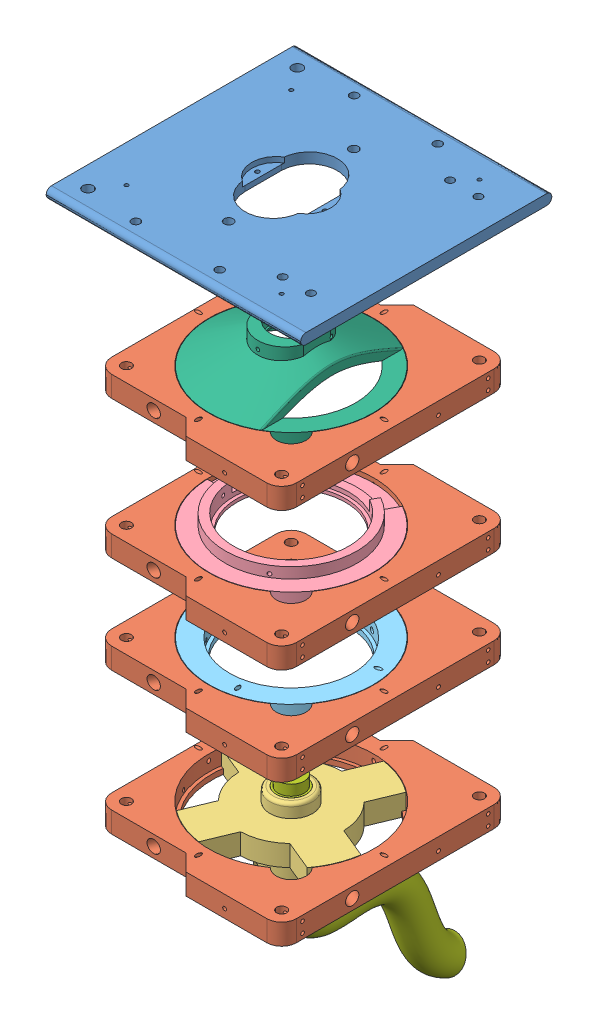
SolidWorks assembly opticalcage, configuration Default. Lengths in mm.
Overall size (154.43 460.49 175.46).
10 component instances, 7 part files, 20 mates.
Components (placement in the parent):
- peltier_TopPlate_off100-1: peltier_TopPlate_off100 [Default] at (-91.0446 13.6016 38.8023) size (154.43 6.35 152.4)
- 100mm_lensholder_and_base_off100-1: 100mm_lensholder_and_base_off100 [Default] at (-18.5446 -316.5942 -37.3977) x (-1 0 0) z (0 0 -1) size (122.18 12.7 138)
- lightpipeholder-1: lightpipeholder [Default] at (-18.5446 -339.6442 -37.3977) x (0.92388 0 0.382683) z (-0.382683 0 0.92388) size (99.4 44 99.4)
- 100mm_lensholder_and_base_off100-2: 100mm_lensholder_and_base_off100 [Default] at (-18.5446 -230.4526 -37.3977) x (-1 0 0) z (0 0 -1) size (122.18 12.7 138)
- 100mm_lensholder_and_base_off100-3: 100mm_lensholder_and_base_off100 [Default] at (-18.5446 -171.4721 -37.3977) x (-1 0 0) z (0 0 -1) size (122.18 12.7 138)
- 100mm_lensholder_and_base_off100-4: 100mm_lensholder_and_base_off100 [Default] at (-18.5446 -87.6141 -37.3977) x (-1 0 0) z (0 0 -1) size (122.18 12.7 138)
- 70mm_irisholder-1: 70mm_irisholder [Default] at (-18.5446 -171.4721 -37.3977) x (-0.382683 0 0.92388) z (-0.92388 0 -0.382683) size (99.4 19.2 99.4)
- 75mm_lensholder-1: 75mm_lensholder [Default] at (-18.5446 -230.4526 -37.3977) x (0.92388 0 0.382683) z (-0.382683 0 0.92388) size (99.4 12.7 99.4)
- 1in_lensholder-1: 1in_lensholder [Default] at (-18.5446 -87.6141 -37.3977) x (0 0 1) z (-1 0 0) size (99.4 36.04 99.4)
- lightpipe-1: lightpipe [Default] at (-18.5446 -289.2942 -37.3977) size (25 151.24 111.76)
Mates (geometry in assembly coordinates):
- Concentric4: concentric aligned: cylinder of peltier_TopPlate_off100-1 through (35.6379 19.9516 22.6023) axis (0 -1 0) radius 1.128; cylinder of 100mm_lensholder_and_base_off100-1 through (35.6379 -303.8942 22.6023) axis (0 -1 0) radius 3.025
- Concentric5: concentric aligned: cylinder of peltier_TopPlate_off100-1 through (-68.5446 19.9516 -87.3977) axis (0 -1 0) radius 1.128; cylinder of 100mm_lensholder_and_base_off100-1 through (-68.5446 -303.8942 -87.3977) axis (0 -1 0) radius 3.025
- Concentric6: concentric aligned: cylinder of 100mm_lensholder_and_base_off100-1 through (-51.5802 -310.2442 42.3571) axis (0.382683 0 -0.92388) radius 2.1; cylinder of lightpipeholder-1 through (-37.564 -310.2442 8.5191) axis (0.382683 0 -0.92388) radius 1.6425
- Concentric7: concentric aligned: cylinder of 100mm_lensholder_and_base_off100-1 through (59.7802 -310.2442 -4.9545) axis (-0.92388 0 -0.382683) radius 3.75; cylinder of lightpipeholder-1 through (27.3722 -310.2442 -18.3783) axis (-0.92388 0 -0.382683) radius 1.6425
- Concentric11: concentric aligned: circle of 100mm_lensholder_and_base_off100-2; circle of 100mm_lensholder_and_base_off100-3
- Concentric12: concentric aligned: circle of 100mm_lensholder_and_base_off100-1; circle of 100mm_lensholder_and_base_off100-2
- Concentric13: concentric aligned: circle of 100mm_lensholder_and_base_off100-3; circle of 100mm_lensholder_and_base_off100-4
- Concentric14: concentric aligned: circle of 100mm_lensholder_and_base_off100-3; circle of 100mm_lensholder_and_base_off100-4
- Concentric15: concentric aligned: circle of 100mm_lensholder_and_base_off100-2; circle of 100mm_lensholder_and_base_off100-3
- Concentric16: concentric aligned: circle of 100mm_lensholder_and_base_off100-1; circle of 100mm_lensholder_and_base_off100-2
- Concentric17: concentric aligned: cylinder of 100mm_lensholder_and_base_off100-2 through (-18.5446 -230.4526 -37.3977) axis (0 -1 0) radius 50; cylinder of 75mm_lensholder-1 through (-18.5446 -230.4526 -37.3977) axis (0 -1 0) radius 37.5
- Concentric18: concentric aligned: cylinder of 100mm_lensholder_and_base_off100-2 through (15.1034 -224.1026 -118.6313) axis (-0.382683 0 0.92388) radius 3.75; cylinder of 75mm_lensholder-1 through (0.4747 -224.1026 -83.3145) axis (-0.382683 0 0.92388) radius 1.6425
- Concentric19: concentric anti-aligned: circle of 100mm_lensholder_and_base_off100-2; cylinder of 75mm_lensholder-1 through (27.3722 -224.1026 -18.3783) axis (-0.92388 0 -0.382683) radius 1.6425
- Concentric20: concentric aligned: cylinder of 100mm_lensholder_and_base_off100-3 through (-18.5446 -171.4721 -37.3977) axis (0 -1 0) radius 50; cylinder of 70mm_irisholder-1 through (-18.5446 -171.4721 -37.3977) axis (0 -1 0) radius 35
- Concentric21: concentric aligned: cylinder of 100mm_lensholder_and_base_off100-3 through (-93.2995 -165.1221 -68.3622) axis (0.92388 0 0.382683) radius 2.1; cylinder of 70mm_irisholder-1 through (-64.4615 -165.1221 -56.4171) axis (0.92388 0 0.382683) radius 1.6425
- Parallel1: parallel aligned: plane of 100mm_lensholder_and_base_off100-4 through (44.6379 -74.9141 22.6023) normal (1 0 0); plane of 1in_lensholder-1 through (-2.7946 -87.6151 -45.5831) normal (1 0 0)
- Concentric22: concentric aligned: cylinder of 100mm_lensholder_and_base_off100-4 through (59.7802 -81.2641 -4.9545) axis (-0.92388 0 -0.382683) radius 3.75; cylinder of 1in_lensholder-1 through (41.4486 -81.2641 -12.5477) axis (-0.92388 0 -0.382683) radius 1.6425
- Concentric23: concentric aligned: circle of 100mm_lensholder_and_base_off100-4; cylinder of 1in_lensholder-1 through (-18.5446 -87.6141 -37.3977) axis (0 -1 0) radius 44.7
- Concentric24: concentric aligned: cylinder of lightpipeholder-1 through (-18.5446 -339.6442 -37.3977) axis (0 -1 0) radius 12.53; cylinder of lightpipe-1 through (-18.5446 -340.1442 -37.3977) axis (0 -1 0) radius 12.5
- Coincident13: coincident anti-aligned: plane of lightpipeholder-1 through (-10.1004 -307.6442 -33.9) normal (0 -1 0); plane of lightpipe-1 through (-9.4446 -307.6442 -37.3977) normal (0 1 0)
